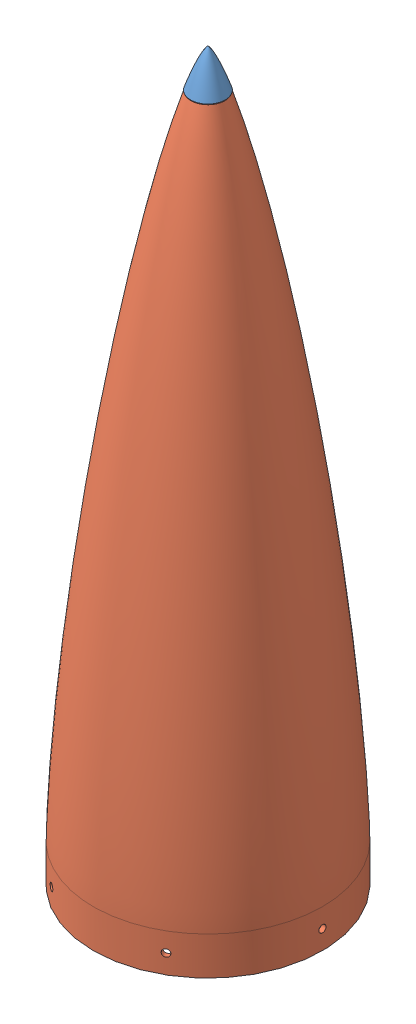
SolidWorks assembly 000077_R01_NOSE_CONE_ASSM, configuration Default. Lengths in mm.
Overall size (304.8 1128.44 304.8).
2 component instances, 2 part files, 1 mates.
Components (placement in the parent):
- 000076-R01_NOSE_CONE_TIP-2: 000076-R01_NOSE_CONE_TIP [Default] at (999.0121 907.2868 995.4719) x (0.00913 -0.999958 0.000472) z (-0.051617 0 0.998667) size (51.36 45.99 45.99)
- 000075-R01_NOSE_CONE-1: 000075-R01_NOSE_CONE [Default] at (999.0121 906.3634 995.4719) x (0 -1 0) z (0 0 1) size (1128.44 304.8 304.8)
Mates (geometry in assembly coordinates):
- Coincident1: coincident: line of assembly; axis of 000076-R01_NOSE_CONE_TIP-2 through (999.0121 890.7312 995.4719) axis (0 1 0); line of 000075-R01_NOSE_CONE-1 through (999.0121 968.0082 995.4719) axis (0 -1 0)
